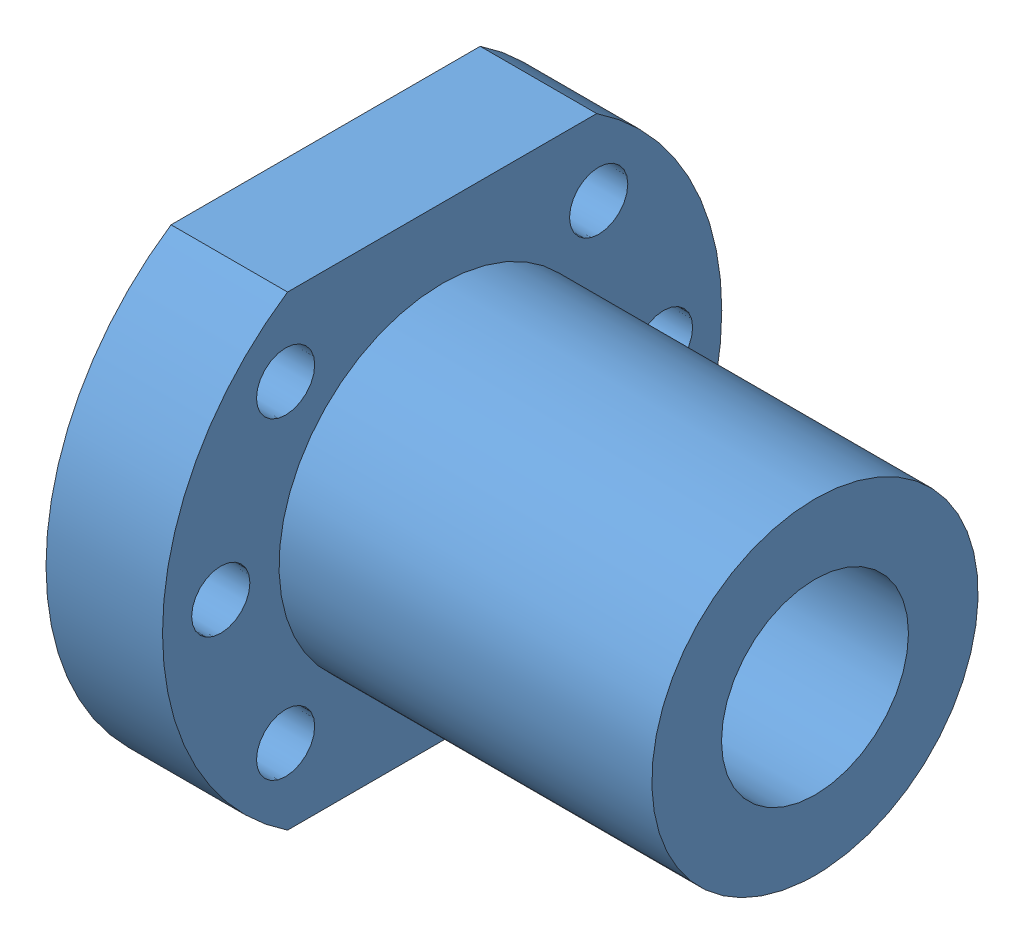
SolidWorks assembly ballscrew_mount_assembly__rev6, configuration Default. Lengths in mm.
Overall size (42 40 48).
2 component instances, 1 part files, 3 mates.
Components (placement in the parent):
- ballscrew_inner_mount__rev6-1: ballscrew_inner_mount__rev6 [Default] at origin size (42 40 48)
- ballscrew_outer_mount-1: ballscrew_outer_mount [Default] at (-370.2219 28.26 -130) x (0 0 -1) z (0 -1 0) (suppressed, hidden)
Mates (geometry in assembly coordinates):
- Concentric1: concentric: cylinder of ballscrew_inner_mount-1 through (10 0 0) axis (1 0 0) radius 14; cylinder of ballscrew_outer_mount-1/mount_1.stp-1 through (10 0 0) axis (1 0 0) radius 14
- Parallel1: parallel: plane of ballscrew_inner_mount-1 through (0 -20 13.2665) normal (0 -1 0); plane of ballscrew_outer_mount-1/mount_1.stp-1 through (10 -20 26) normal (0 -1 0)
- Coincident2: coincident anti-aligned: plane of ballscrew_inner_mount-1 through (10 0 0) normal (1 0 0); plane of ballscrew_outer_mount-1/mount_1.stp-1 through (10 0 0) normal (-1 0 0)
